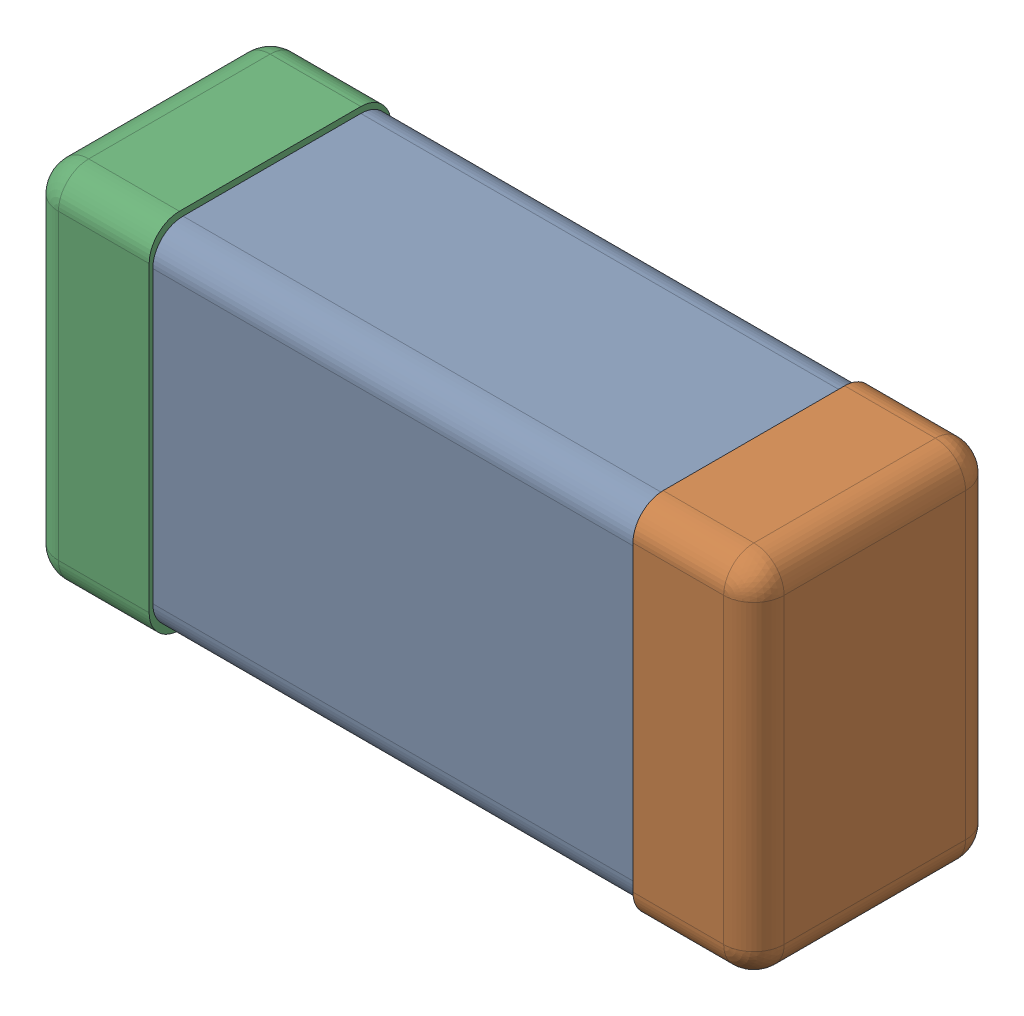
SolidWorks assembly C0201_020, configuration Standard. Lengths in mm.
Overall size (0.6 0.3 0.2).
4 component instances, 3 part files, 0 mates.
Components (placement in the parent):
- C0201_020_1-1: C0201_020_1 [Standard] at origin size (0.6 0.3 0.2)
  - Part 3_2-1: Part 3_2 [Standard] at (0 0 -7.3015) size (0.5 0.29 0.2)
  - Part 2_2-1: Part 2_2 [Standard] at (0 0 -7.3) size (0.1 0.3 0.2)
  - Part 1_2-1: Part 1_2 [Standard] at (0 0 -7.3) size (0.1 0.3 0.2)
